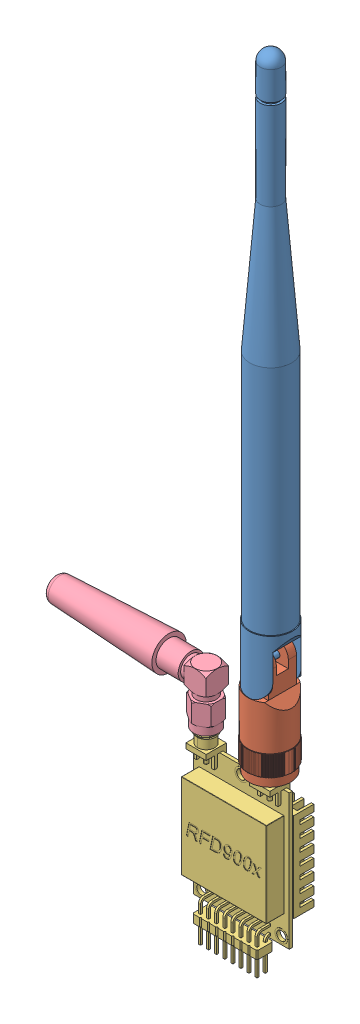
SolidWorks assembly Radio Assembly_AvBay_Mid, configuration Default. Lengths in mm.
Overall size (74.8 251.75 15.33).
4 component instances, 4 part files, 13 mates.
Components (placement in the parent):
- Radio - Long Antenna-1: Radio - Long Antenna [Default] at (17.0104 48.5775 1.0712) x (-1 0 0) z (0 0 -1) size (13.47 173.15 13.47)
- Radio - Long Antenna Base-1: Radio - Long Antenna Base [Default] at (10 25.4 1.0712) x (-1 0 0) z (0 0 -1) size (13.92 35.03 13.92)
- Radio - RFD900X-1: Radio - RFD900X [Default] at origin size (30.8 60.8 12.8)
- GSM_ANTENNA_900MHZ-2: GSM_ANTENNA_900MHZ [Default] at (-14.7196 44.87 -2.4697) x (0 1 0) z (-0.008629 0 0.999963) size (19.26 51.65 10.7)
Mates (geometry in assembly coordinates):
- Coincident1: coordinate: point of Radio - RFD900X-1
- Concentric1: concentric anti-aligned: cylinder of Radio - Long Antenna Base-1 through (10 40.4 1.0712) axis (0 1 0) radius 2.775; cylinder of Radio - RFD900X-1 through (10 22.9 1.0712) axis (0 -1 0) radius 2.675
- Distance1: distance = 2.5 mm anti-aligned: plane of Radio - Long Antenna Base-1 through (16.477 25.4 1.0712) normal (0 -1 0); plane of Radio - RFD900X-1 through (6.825 22.9 4.2462) normal (0 1 0)
- Coincident3: coincident aligned: plane of Radio - Long Antenna-1 through (17.0104 48.5775 1.0712) normal (0 0 -1); plane of Radio - Long Antenna Base-1 through (10 25.4 1.0712) normal (0 0 -1)
- Concentric3: concentric anti-aligned: cylinder of Radio - RFD900X-1 through (-10 22.9 1.0712) axis (0 -1 0) radius 2.675; cylinder of Radio - Short Antenna-1 through (-10 32.9584 1.0712) axis (0 1 0) radius 3.3528
- Distance2: distance = 1.524 mm anti-aligned: plane of Radio - Short Antenna-1 through (-6.1646 24.424 1.0712) normal (0 -1 0); plane of Radio - RFD900X-1 through (-13.175 22.9 4.2462) normal (0 1 0)
- Parallel1: parallel aligned: plane of Radio - Short Antenna-1 through (-10 32.9584 1.0712) normal (0 0 1)
- Parallel2: parallel anti-aligned: plane of Radio - Long Antenna Base-1 through (10 25.4 1.0712) normal (-1 0 0)
- Coincident4: coincident anti-aligned: plane of Radio - Long Antenna-1 through (6.0757 48.5775 1.0712) normal (1 0 0); plane of Radio - Long Antenna Base-1 through (6.0757 56.5023 -3.3611) normal (-1 0 0)
- Coincident6: coincident anti-aligned: plane of Radio - Long Antenna-1 through (10.2731 48.5775 1.0712) normal (0 -1 0); plane of Radio - Long Antenna Base-1 through (16.8199 48.5775 1.0712) normal (0 1 0)
- Coincident7: coincident anti-aligned: plane of Radio - RFD900X-1 through (-10 30.77 -1.5038) normal (0 1 0); plane of GSM_ANTENNA_900MHZ-1 through (-7.5368 30.77 -6.7206) normal (0 -1 0)
- Coincident8: coincident anti-aligned: plane of Radio - RFD900X-1 through (-10 30.77 -1.5038) normal (0 1 0); plane of GSM_ANTENNA_900MHZ-2 through (-10 30.77 1.0712) normal (0 -1 0)
- Concentric5: concentric anti-aligned: cylinder of Radio - RFD900X-1 through (-10 22.9 1.0712) axis (0 -1 0) radius 3.12; cylinder of GSM_ANTENNA_900MHZ-2 through (-10 27.47 1.0712) axis (0 1 0) radius 3.25
